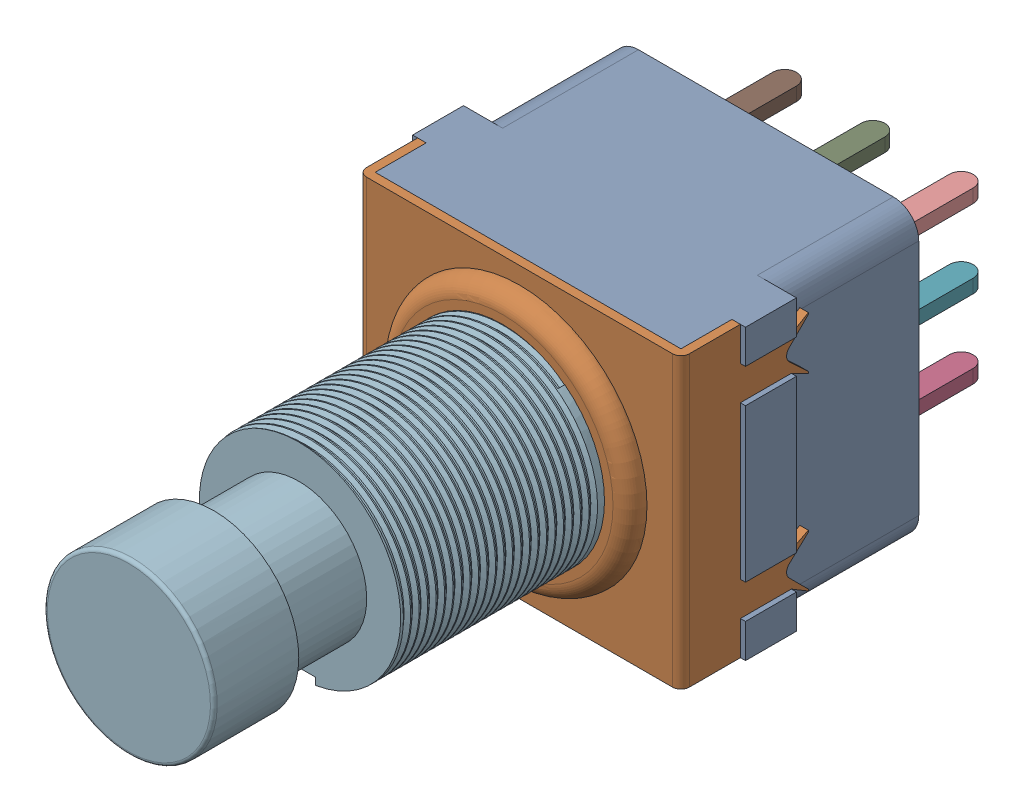
SolidWorks assembly FSW2, configuration Default. Lengths in mm.
Overall size (19.6 17 44.5).
13 component instances, 4 part files, 0 mates.
Components (placement in the parent):
- 3PDT-1: 3PDT [Default] at (230.2994 72.0412 1.27) x (1 0 0) z (0 0 1) size (19.6 17 44.5)
  - 3PDT Body-1: 3PDT Body [Default] at (0 -2.1806 0.7727) size (19.6 17 15)
  - 3PDT Cover-1: 3PDT Cover [Default] at (-0.5 14.8194 11.7727) x (1 0 0) z (0 -1 0) size (19 8.5 17)
  - 3PDT Pin-1: 3PDT Pin [Default] at (7 1.7194 0.7727) x (1 0 0) z (0 1 0) size (4 7 0.8)
  - 3PDT Pin-2: 3PDT Pin [Default] at (12.2 1.7194 0.7727) x (1 0 0) z (0 1 0) size (4 7 0.8)
  - 3PDT Pin-3: 3PDT Pin [Default] at (1.8 1.7194 0.7727) x (1 0 0) z (0 1 0) size (4 7 0.8)
  - 3PDT Pin-4: 3PDT Pin [Default] at (7 6.3194 0.7727) x (1 0 0) z (0 1 0) size (4 7 0.8)
  - 3PDT Pin-5: 3PDT Pin [Default] at (12.2 6.3194 0.7727) x (1 0 0) z (0 1 0) size (4 7 0.8)
  - 3PDT Pin-6: 3PDT Pin [Default] at (1.8 6.3194 0.7727) x (1 0 0) z (0 1 0) size (4 7 0.8)
  - 3PDT Pin-7: 3PDT Pin [Default] at (7 10.9194 0.7727) x (1 0 0) z (0 1 0) size (4 7 0.8)
  - 3PDT Pin-8: 3PDT Pin [Default] at (12.2 10.9194 0.7727) x (1 0 0) z (0 1 0) size (4 7 0.8)
  - 3PDT Pin-9: 3PDT Pin [Default] at (1.8 10.9194 0.7727) x (1 0 0) z (0 1 0) size (4 7 0.8)
  - 3PDT Schalter-1: 3PDT Schalter [Default] at (9 6.3194 28.2727) x (0 -1 0) z (0 0 1) size (12 12.17 22.2)
